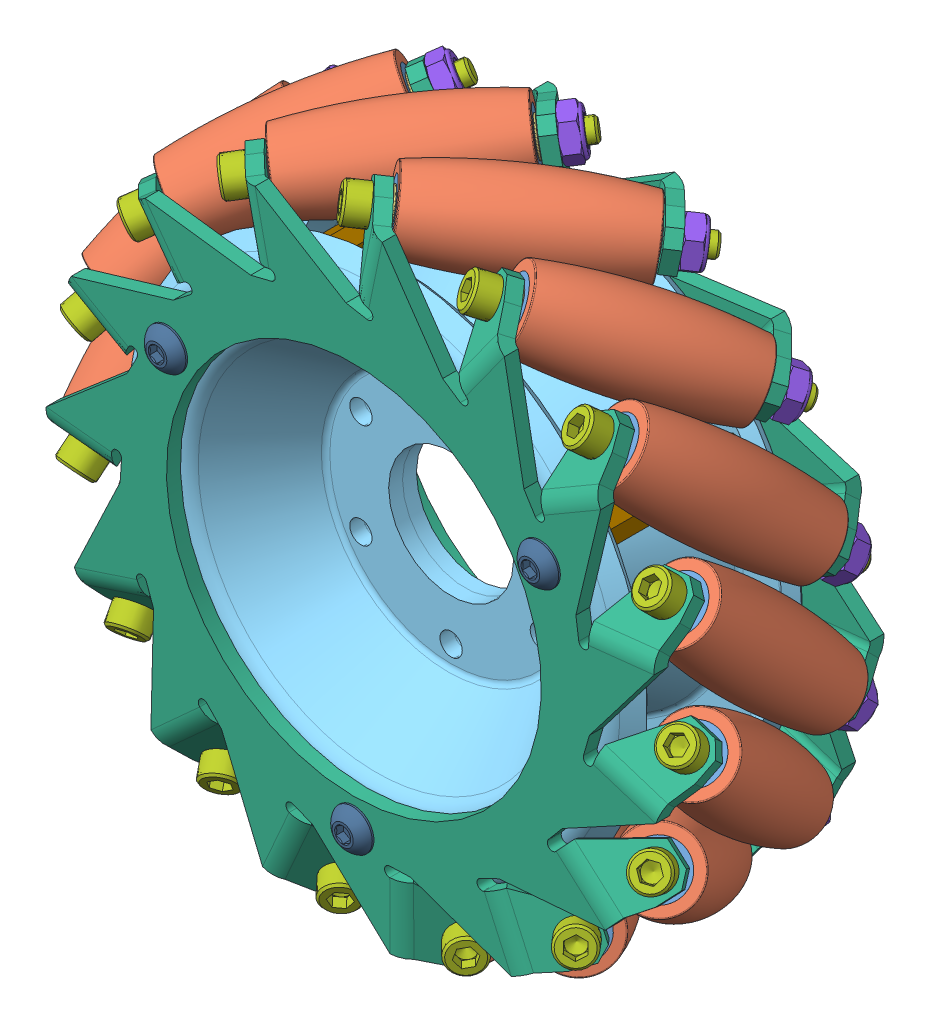
SolidWorks assembly am-3479La 6 SR Mecanum (LEFT with Standoffs), configuration Default. Lengths in mm.
Overall size (158.29 158.03 55.95).
134 component instances, 10 part files, 0 mates.
Components (placement in the parent):
- am-3479La 6 SR Mecanum Left with Standoffs.STEP-1: am-3479La 6 SR Mecanum Left with Standoffs.STEP [Default] at origin size (158.29 158.03 55.95)
  - am-3479_roller.STEP-1: am-3479_roller.STEP [Default] at (-1.2868 -63.2802 -0.1615) x (-0.034273 0.998836 0.033931) z (0.706278 0.048228 -0.70629) size (19.48 44.35 19.48)
    - am-3698_core PC.STEP-1: am-3698_core PC.STEP [Default] at (-2.9239 1.0394 0.8367) size (14.92 43.18 14.92)
    - am-3698_skin TPU v2.STEP-1: am-3698_skin TPU v2.STEP [Default] at (-2.9239 22.6294 0.8367) x (1 0 0) z (0 1 0) size (19.48 19.48 43.18)
    - am-0603 MBC Bushing MU04TH04.STEP-1: am-0603 MBC Bushing MU04TH04.STEP [Default] at (-2.9239 -20.9316 0.8367) x (0 1 0) z (0 0 1) size (6.35 7.94 7.94)
    - am-0603 MBC Bushing MU04TH04.STEP-2: am-0603 MBC Bushing MU04TH04.STEP [Default] at (-2.9239 16.6604 0.8367) x (0 1 0) z (-0.707574 0 0.70664) size (6.35 7.94 7.94)
    - am-0701a 6IN SR Roller Axle.STEP-1: am-0701a 6IN SR Roller Axle.STEP [Default] at (-2.9239 23.2136 0.8367) x (0 -1 0) z (0 0 1) size (44.35 6.35 6.35)
  - am-3479_roller-1.STEP-1: am-3479_roller-1.STEP [Default] at (-26.9139 -57.2859 -0.1615) x (0.374953 0.926423 0.033931) z (0.664833 -0.243211 -0.70629) size (19.48 44.35 19.48)
    - am-3698_core PC.STEP-1: am-3698_core PC.STEP [Default] at (-2.9239 1.0394 0.8367) size (14.92 43.18 14.92)
    - am-3698_skin TPU v2.STEP-1: am-3698_skin TPU v2.STEP [Default] at (-2.9239 22.6294 0.8367) x (1 0 0) z (0 1 0) size (19.48 19.48 43.18)
    - am-0603 MBC Bushing MU04TH04.STEP-1: am-0603 MBC Bushing MU04TH04.STEP [Default] at (-2.9239 -20.9316 0.8367) x (0 1 0) z (0 0 1) size (6.35 7.94 7.94)
    - am-0603 MBC Bushing MU04TH04.STEP-2: am-0603 MBC Bushing MU04TH04.STEP [Default] at (-2.9239 16.6604 0.8367) x (0 1 0) z (-0.707574 0 0.70664) size (6.35 7.94 7.94)
    - am-0701a 6IN SR Roller Axle.STEP-1: am-0701a 6IN SR Roller Axle.STEP [Default] at (-2.9239 23.2136 0.8367) x (0 -1 0) z (0 0 1) size (44.35 6.35 6.35)
  - am-3479_roller-2.STEP-1: am-3479_roller-2.STEP [Default] at (-47.8873 -41.3864 -0.1615) x (0.719347 0.693822 0.033931) z (0.508432 -0.492596 -0.70629) size (19.48 44.35 19.48)
    - am-3698_core PC.STEP-1: am-3698_core PC.STEP [Default] at (-2.9239 1.0394 0.8367) size (14.92 43.18 14.92)
    - am-3698_skin TPU v2.STEP-1: am-3698_skin TPU v2.STEP [Default] at (-2.9239 22.6294 0.8367) x (1 0 0) z (0 1 0) size (19.48 19.48 43.18)
    - am-0603 MBC Bushing MU04TH04.STEP-1: am-0603 MBC Bushing MU04TH04.STEP [Default] at (-2.9239 -20.9316 0.8367) x (0 1 0) z (0 0 1) size (6.35 7.94 7.94)
    - am-0603 MBC Bushing MU04TH04.STEP-2: am-0603 MBC Bushing MU04TH04.STEP [Default] at (-2.9239 16.6604 0.8367) x (0 1 0) z (-0.707574 0 0.70664) size (6.35 7.94 7.94)
    - am-0701a 6IN SR Roller Axle.STEP-1: am-0701a 6IN SR Roller Axle.STEP [Default] at (-2.9239 23.2136 0.8367) x (0 -1 0) z (0 0 1) size (44.35 6.35 6.35)
  - am-3479_roller-3.STEP-1: am-3479_roller-3.STEP [Default] at (-60.5806 -18.3309 -0.1615) x (0.939359 0.341253 0.033931) z (0.264119 -0.656807 -0.70629) size (19.48 44.35 19.48)
    - am-3698_core PC.STEP-1: am-3698_core PC.STEP [Default] at (-2.9239 1.0394 0.8367) size (14.92 43.18 14.92)
    - am-3698_skin TPU v2.STEP-1: am-3698_skin TPU v2.STEP [Default] at (-2.9239 22.6294 0.8367) x (1 0 0) z (0 1 0) size (19.48 19.48 43.18)
    - am-0603 MBC Bushing MU04TH04.STEP-1: am-0603 MBC Bushing MU04TH04.STEP [Default] at (-2.9239 -20.9316 0.8367) x (0 1 0) z (0 0 1) size (6.35 7.94 7.94)
    - am-0603 MBC Bushing MU04TH04.STEP-2: am-0603 MBC Bushing MU04TH04.STEP [Default] at (-2.9239 16.6604 0.8367) x (0 1 0) z (-0.707574 0 0.70664) size (6.35 7.94 7.94)
    - am-0701a 6IN SR Roller Axle.STEP-1: am-0701a 6IN SR Roller Axle.STEP [Default] at (-2.9239 23.2136 0.8367) x (0 -1 0) z (0 0 1) size (44.35 6.35 6.35)
  - am-3479_roller-4.STEP-1: am-3479_roller-4.STEP [Default] at (-62.799 7.8943 -0.1615) x (0.996947 -0.070321 0.033931) z (-0.025863 -0.70745 -0.70629) size (19.48 44.35 19.48)
    - am-3698_core PC.STEP-1: am-3698_core PC.STEP [Default] at (-2.9239 1.0394 0.8367) size (14.92 43.18 14.92)
    - am-3698_skin TPU v2.STEP-1: am-3698_skin TPU v2.STEP [Default] at (-2.9239 22.6294 0.8367) x (1 0 0) z (0 1 0) size (19.48 19.48 43.18)
    - am-0603 MBC Bushing MU04TH04.STEP-1: am-0603 MBC Bushing MU04TH04.STEP [Default] at (-2.9239 -20.9316 0.8367) x (0 1 0) z (0 0 1) size (6.35 7.94 7.94)
    - am-0603 MBC Bushing MU04TH04.STEP-2: am-0603 MBC Bushing MU04TH04.STEP [Default] at (-2.9239 16.6604 0.8367) x (0 1 0) z (-0.707574 0 0.70664) size (6.35 7.94 7.94)
    - am-0701a 6IN SR Roller Axle.STEP-1: am-0701a 6IN SR Roller Axle.STEP [Default] at (-2.9239 23.2136 0.8367) x (0 -1 0) z (0 0 1) size (44.35 6.35 6.35)
  - am-3479_roller-5.STEP-1: am-3479_roller-5.STEP [Default] at (-54.1588 32.7544 -0.1615) x (0.882154 -0.469737 0.033931) z (-0.311373 -0.635768 -0.70629) size (19.48 44.35 19.48)
    - am-3698_core PC.STEP-1: am-3698_core PC.STEP [Default] at (-2.9239 1.0394 0.8367) size (14.92 43.18 14.92)
    - am-3698_skin TPU v2.STEP-1: am-3698_skin TPU v2.STEP [Default] at (-2.9239 22.6294 0.8367) x (1 0 0) z (0 1 0) size (19.48 19.48 43.18)
    - am-0603 MBC Bushing MU04TH04.STEP-1: am-0603 MBC Bushing MU04TH04.STEP [Default] at (-2.9239 -20.9316 0.8367) x (0 1 0) z (0 0 1) size (6.35 7.94 7.94)
    - am-0603 MBC Bushing MU04TH04.STEP-2: am-0603 MBC Bushing MU04TH04.STEP [Default] at (-2.9239 16.6604 0.8367) x (0 1 0) z (-0.707574 0 0.70664) size (6.35 7.94 7.94)
    - am-0701a 6IN SR Roller Axle.STEP-1: am-0701a 6IN SR Roller Axle.STEP [Default] at (-2.9239 23.2136 0.8367) x (0 -1 0) z (0 0 1) size (44.35 6.35 6.35)
  - am-3479_roller-6.STEP-1: am-3479_roller-6.STEP [Default] at (-36.1541 51.9511 -0.1615) x (0.614829 -0.78793 0.033931) z (-0.543043 -0.454157 -0.70629) size (19.48 44.35 19.48)
    - am-3698_core PC.STEP-1: am-3698_core PC.STEP [Default] at (-2.9239 1.0394 0.8367) size (14.92 43.18 14.92)
    - am-3698_skin TPU v2.STEP-1: am-3698_skin TPU v2.STEP [Default] at (-2.9239 22.6294 0.8367) x (1 0 0) z (0 1 0) size (19.48 19.48 43.18)
    - am-0603 MBC Bushing MU04TH04.STEP-1: am-0603 MBC Bushing MU04TH04.STEP [Default] at (-2.9239 -20.9316 0.8367) x (0 1 0) z (0 0 1) size (6.35 7.94 7.94)
    - am-0603 MBC Bushing MU04TH04.STEP-2: am-0603 MBC Bushing MU04TH04.STEP [Default] at (-2.9239 16.6604 0.8367) x (0 1 0) z (-0.707574 0 0.70664) size (6.35 7.94 7.94)
    - am-0701a 6IN SR Roller Axle.STEP-1: am-0701a 6IN SR Roller Axle.STEP [Default] at (-2.9239 23.2136 0.8367) x (0 -1 0) z (0 0 1) size (44.35 6.35 6.35)
  - am-3479_roller-7.STEP-1: am-3479_roller-7.STEP [Default] at (-11.898 62.1649 -0.1615) x (0.241194 -0.969884 0.033931) z (-0.680817 -0.194017 -0.70629) size (19.48 44.35 19.48)
    - am-3698_core PC.STEP-1: am-3698_core PC.STEP [Default] at (-2.9239 1.0394 0.8367) size (14.92 43.18 14.92)
    - am-3698_skin TPU v2.STEP-1: am-3698_skin TPU v2.STEP [Default] at (-2.9239 22.6294 0.8367) x (1 0 0) z (0 1 0) size (19.48 19.48 43.18)
    - am-0603 MBC Bushing MU04TH04.STEP-1: am-0603 MBC Bushing MU04TH04.STEP [Default] at (-2.9239 -20.9316 0.8367) x (0 1 0) z (0 0 1) size (6.35 7.94 7.94)
    - am-0603 MBC Bushing MU04TH04.STEP-2: am-0603 MBC Bushing MU04TH04.STEP [Default] at (-2.9239 16.6604 0.8367) x (0 1 0) z (-0.707574 0 0.70664) size (6.35 7.94 7.94)
    - am-0701a 6IN SR Roller Axle.STEP-1: am-0701a 6IN SR Roller Axle.STEP [Default] at (-2.9239 23.2136 0.8367) x (0 -1 0) z (0 0 1) size (44.35 6.35 6.35)
  - am-3479_roller-8.STEP-1: am-3479_roller-8.STEP [Default] at (14.4153 61.6298 -0.1615) x (-0.174146 -0.984135 0.033931) z (-0.700871 0.09967 -0.70629) size (19.48 44.35 19.48)
    - am-3698_core PC.STEP-1: am-3698_core PC.STEP [Default] at (-2.9239 1.0394 0.8367) size (14.92 43.18 14.92)
    - am-3698_skin TPU v2.STEP-1: am-3698_skin TPU v2.STEP [Default] at (-2.9239 22.6294 0.8367) x (1 0 0) z (0 1 0) size (19.48 19.48 43.18)
    - am-0603 MBC Bushing MU04TH04.STEP-1: am-0603 MBC Bushing MU04TH04.STEP [Default] at (-2.9239 -20.9316 0.8367) x (0 1 0) z (0 0 1) size (6.35 7.94 7.94)
    - am-0603 MBC Bushing MU04TH04.STEP-2: am-0603 MBC Bushing MU04TH04.STEP [Default] at (-2.9239 16.6604 0.8367) x (0 1 0) z (-0.707574 0 0.70664) size (6.35 7.94 7.94)
    - am-0701a 6IN SR Roller Axle.STEP-1: am-0701a 6IN SR Roller Axle.STEP [Default] at (-2.9239 23.2136 0.8367) x (0 -1 0) z (0 0 1) size (44.35 6.35 6.35)
  - am-3479_roller-9.STEP-1: am-3479_roller-9.STEP [Default] at (38.2362 50.4384 -0.1615) x (-0.559374 -0.828221 0.033931) z (-0.599738 0.376123 -0.70629) size (19.48 44.35 19.48)
    - am-3698_core PC.STEP-1: am-3698_core PC.STEP [Default] at (-2.9239 1.0394 0.8367) size (14.92 43.18 14.92)
    - am-3698_skin TPU v2.STEP-1: am-3698_skin TPU v2.STEP [Default] at (-2.9239 22.6294 0.8367) x (1 0 0) z (0 1 0) size (19.48 19.48 43.18)
    - am-0603 MBC Bushing MU04TH04.STEP-1: am-0603 MBC Bushing MU04TH04.STEP [Default] at (-2.9239 -20.9316 0.8367) x (0 1 0) z (0 0 1) size (6.35 7.94 7.94)
    - am-0603 MBC Bushing MU04TH04.STEP-2: am-0603 MBC Bushing MU04TH04.STEP [Default] at (-2.9239 16.6604 0.8367) x (0 1 0) z (-0.707574 0 0.70664) size (6.35 7.94 7.94)
    - am-0701a 6IN SR Roller Axle.STEP-1: am-0701a 6IN SR Roller Axle.STEP [Default] at (-2.9239 23.2136 0.8367) x (0 -1 0) z (0 0 1) size (44.35 6.35 6.35)
  - am-3479_roller-10.STEP-1: am-3479_roller-10.STEP [Default] at (55.4456 30.5257 -0.1615) x (-0.847881 -0.5291 0.033931) z (-0.394905 0.587541 -0.70629) size (19.48 44.35 19.48)
    - am-3698_core PC.STEP-1: am-3698_core PC.STEP [Default] at (-2.9239 1.0394 0.8367) size (14.92 43.18 14.92)
    - am-3698_skin TPU v2.STEP-1: am-3698_skin TPU v2.STEP [Default] at (-2.9239 22.6294 0.8367) x (1 0 0) z (0 1 0) size (19.48 19.48 43.18)
    - am-0603 MBC Bushing MU04TH04.STEP-1: am-0603 MBC Bushing MU04TH04.STEP [Default] at (-2.9239 -20.9316 0.8367) x (0 1 0) z (0 0 1) size (6.35 7.94 7.94)
    - am-0603 MBC Bushing MU04TH04.STEP-2: am-0603 MBC Bushing MU04TH04.STEP [Default] at (-2.9239 16.6604 0.8367) x (0 1 0) z (-0.707574 0 0.70664) size (6.35 7.94 7.94)
    - am-0701a 6IN SR Roller Axle.STEP-1: am-0701a 6IN SR Roller Axle.STEP [Default] at (-2.9239 23.2136 0.8367) x (0 -1 0) z (0 0 1) size (44.35 6.35 6.35)
  - am-3479_roller-11.STEP-1: am-3479_roller-11.STEP [Default] at (63.068 5.3349 -0.1615) x (-0.989782 -0.138492 0.033931) z (-0.121789 0.697368 -0.70629) size (19.48 44.35 19.48)
    - am-3698_core PC.STEP-1: am-3698_core PC.STEP [Default] at (-2.9239 1.0394 0.8367) size (14.92 43.18 14.92)
    - am-3698_skin TPU v2.STEP-1: am-3698_skin TPU v2.STEP [Default] at (-2.9239 22.6294 0.8367) x (1 0 0) z (0 1 0) size (19.48 19.48 43.18)
    - am-0603 MBC Bushing MU04TH04.STEP-1: am-0603 MBC Bushing MU04TH04.STEP [Default] at (-2.9239 -20.9316 0.8367) x (0 1 0) z (0 0 1) size (6.35 7.94 7.94)
    - am-0603 MBC Bushing MU04TH04.STEP-2: am-0603 MBC Bushing MU04TH04.STEP [Default] at (-2.9239 16.6604 0.8367) x (0 1 0) z (-0.707574 0 0.70664) size (6.35 7.94 7.94)
    - am-0701a 6IN SR Roller Axle.STEP-1: am-0701a 6IN SR Roller Axle.STEP [Default] at (-2.9239 23.2136 0.8367) x (0 -1 0) z (0 0 1) size (44.35 6.35 6.35)
  - am-3479_roller-12.STEP-1: am-3479_roller-12.STEP [Default] at (59.7854 -20.7784 -0.1615) x (-0.960541 0.276062 0.033931) z (0.172385 0.686613 -0.70629) size (19.48 44.35 19.48)
    - am-3698_core PC.STEP-1: am-3698_core PC.STEP [Default] at (-2.9239 1.0394 0.8367) size (14.92 43.18 14.92)
    - am-3698_skin TPU v2.STEP-1: am-3698_skin TPU v2.STEP [Default] at (-2.9239 22.6294 0.8367) x (1 0 0) z (0 1 0) size (19.48 19.48 43.18)
    - am-0603 MBC Bushing MU04TH04.STEP-1: am-0603 MBC Bushing MU04TH04.STEP [Default] at (-2.9239 -20.9316 0.8367) x (0 1 0) z (0 0 1) size (6.35 7.94 7.94)
    - am-0603 MBC Bushing MU04TH04.STEP-2: am-0603 MBC Bushing MU04TH04.STEP [Default] at (-2.9239 16.6604 0.8367) x (0 1 0) z (-0.707574 0 0.70664) size (6.35 7.94 7.94)
    - am-0701a 6IN SR Roller Axle.STEP-1: am-0701a 6IN SR Roller Axle.STEP [Default] at (-2.9239 23.2136 0.8367) x (0 -1 0) z (0 0 1) size (44.35 6.35 6.35)
  - am-3479_roller-13.STEP-1: am-3479_roller-13.STEP [Default] at (46.1653 -43.2989 -0.1615) x (-0.765213 0.642882 0.033931) z (0.436752 0.557137 -0.70629) size (19.48 44.35 19.48)
    - am-3698_core PC.STEP-1: am-3698_core PC.STEP [Default] at (-2.9239 1.0394 0.8367) size (14.92 43.18 14.92)
    - am-3698_skin TPU v2.STEP-1: am-3698_skin TPU v2.STEP [Default] at (-2.9239 22.6294 0.8367) x (1 0 0) z (0 1 0) size (19.48 19.48 43.18)
    - am-0603 MBC Bushing MU04TH04.STEP-1: am-0603 MBC Bushing MU04TH04.STEP [Default] at (-2.9239 -20.9316 0.8367) x (0 1 0) z (0 0 1) size (6.35 7.94 7.94)
    - am-0603 MBC Bushing MU04TH04.STEP-2: am-0603 MBC Bushing MU04TH04.STEP [Default] at (-2.9239 16.6604 0.8367) x (0 1 0) z (-0.707574 0 0.70664) size (6.35 7.94 7.94)
    - am-0701a 6IN SR Roller Axle.STEP-1: am-0701a 6IN SR Roller Axle.STEP [Default] at (-2.9239 23.2136 0.8367) x (0 -1 0) z (0 0 1) size (44.35 6.35 6.35)
  - am-3479_roller-14.STEP-1: am-3479_roller-14.STEP [Default] at (24.5628 -58.3327 -0.1615) x (-0.437573 0.898542 0.033931) z (0.625601 0.331327 -0.70629) size (19.48 44.35 19.48)
    - am-3698_core PC.STEP-1: am-3698_core PC.STEP [Default] at (-2.9239 1.0394 0.8367) size (14.92 43.18 14.92)
    - am-3698_skin TPU v2.STEP-1: am-3698_skin TPU v2.STEP [Default] at (-2.9239 22.6294 0.8367) x (1 0 0) z (0 1 0) size (19.48 19.48 43.18)
    - am-0603 MBC Bushing MU04TH04.STEP-1: am-0603 MBC Bushing MU04TH04.STEP [Default] at (-2.9239 -20.9316 0.8367) x (0 1 0) z (0 0 1) size (6.35 7.94 7.94)
    - am-0603 MBC Bushing MU04TH04.STEP-2: am-0603 MBC Bushing MU04TH04.STEP [Default] at (-2.9239 16.6604 0.8367) x (0 1 0) z (-0.707574 0 0.70664) size (6.35 7.94 7.94)
    - am-0701a 6IN SR Roller Axle.STEP-1: am-0701a 6IN SR Roller Axle.STEP [Default] at (-2.9239 23.2136 0.8367) x (0 -1 0) z (0 0 1) size (44.35 6.35 6.35)
  - ip-3479a_hub.STEP-1: ip-3479a_hub.STEP [Default] x (0 0 1) z (1 0 0) size (22.23 118.71 118.71)
  - ip-3479a_hub.STEP-2: ip-3479a_hub.STEP [Default] x (0 0 -1) z (-1 0 0) size (22.23 118.71 118.71)
  - am-0676a Left Plate HD.STEP-1: am-0676a Left Plate HD.STEP [Default] at (0 0 23.114) x (-0.999437 -0.033548 0) z (0 0 1) size (146.64 146.22 13.05)
  - am-0676a Left Plate HD.STEP-2: am-0676a Left Plate HD.STEP [Default] at (0 0 -23.114) x (0.99946 -0.032864 0) z (0 0 -1) size (146.64 146.22 13.05)
  - 10-32x2250_shcs_HX-SHCS 0.19-32x1.375x1-C.STEP-1: 10-32x2250_shcs_HX-SHCS 0.19-32x1.375x1-C.STEP [Default] at (21.4977 -66.1527 21.2417) x (-0.707105 -0.000242 -0.707109) z (0.143048 -0.979373 -0.142712) size (61.98 7.94 7.94)
  - 10-32 Nylock Jam Nut_90633A411.STEP-1: 10-32 Nylock Jam Nut_90633A411.STEP [Default] at (-17.791 -66.1662 -18.0472) x (0.176781 0.968184 -0.177112) z (-0.684654 0.25024 0.684564) size (9.55 4.38 11.02)
  - 10-32 Nylock Jam Nut_90633A411.STEP-2: 10-32 Nylock Jam Nut_90633A411.STEP [Default] at (-43.1651 -53.2096 -18.0472) x (0.555294 0.812576 -0.177112) z (-0.523681 0.50708 0.684564) size (9.55 4.38 11.02)
  - 10-32 Nylock Jam Nut_90633A411.STEP-3: 10-32 Nylock Jam Nut_90633A411.STEP [Default] at (-61.0755 -31.0525 -18.0472) x (0.837791 0.516467 -0.177112) z (-0.272158 0.676241 0.684564) size (9.55 4.38 11.02)
  - 10-32 Nylock Jam Nut_90633A411.STEP-4: 10-32 Nylock Jam Nut_90633A411.STEP [Default] at (-68.4255 -3.5263 -18.0472) x (0.975426 0.131056 -0.177112) z (0.026423 0.728473 0.684564) size (9.55 4.38 11.02)
  - 10-32 Nylock Jam Nut_90633A411.STEP-5: 10-32 Nylock Jam Nut_90633A411.STEP [Default] at (-63.9441 24.6098 -18.0472) x (0.944401 -0.277016 -0.177112) z (0.320435 0.654747 0.684564) size (9.55 4.38 11.02)
  - 10-32 Nylock Jam Nut_90633A411.STEP-6: 10-32 Nylock Jam Nut_90633A411.STEP [Default] at (-48.4061 48.4905 -18.0472) x (0.750081 -0.637189 -0.177112) z (0.559041 0.467808 0.684564) size (9.55 4.38 11.02)
  - 10-32 Nylock Jam Nut_90633A411.STEP-7: 10-32 Nylock Jam Nut_90633A411.STEP [Default] at (-24.4983 63.9868 -18.0472) x (0.426065 -0.887187 -0.177112) z (0.700984 0.199981 0.684564) size (9.55 4.38 11.02)
  - 10-32 Nylock Jam Nut_90633A411.STEP-8: 10-32 Nylock Jam Nut_90633A411.STEP [Default] at (3.6455 68.4192 -18.0472) x (0.028379 -0.983782 -0.177112) z (0.721721 -0.102424 0.684564) size (9.55 4.38 11.02)
  - 10-32 Nylock Jam Nut_90633A411.STEP-9: 10-32 Nylock Jam Nut_90633A411.STEP [Default] at (31.1589 61.0213 -18.0472) x (-0.374215 -0.910272 -0.177112) z (0.617665 -0.387119 0.684564) size (9.55 4.38 11.02)
  - 10-32 Nylock Jam Nut_90633A411.STEP-10: 10-32 Nylock Jam Nut_90633A411.STEP [Default] at (53.2847 43.0723 -18.0472) x (-0.712103 -0.679368 -0.177112) z (0.40681 -0.604878 0.684564) size (9.55 4.38 11.02)
  - 10-32 Nylock Jam Nut_90633A411.STEP-11: 10-32 Nylock Jam Nut_90633A411.STEP [Default] at (66.1971 17.6757 -18.0472) x (-0.926862 -0.330995 -0.177112) z (0.125613 -0.718048 0.684564) size (9.55 4.38 11.02)
  - 10-32 Nylock Jam Nut_90633A411.STEP-12: 10-32 Nylock Jam Nut_90633A411.STEP [Default] at (67.6634 -10.7773 -18.0472) x (-0.981359 0.07461 -0.177112) z (-0.177303 -0.707061 0.684564) size (9.55 4.38 11.02)
  - 10-32 Nylock Jam Nut_90633A411.STEP-13: 10-32 Nylock Jam Nut_90633A411.STEP [Default] at (57.4301 -37.3667 -18.0472) x (-0.866169 0.467314 -0.177112) z (-0.449562 -0.573817 0.684564) size (9.55 4.38 11.02)
  - 10-32 Nylock Jam Nut_90633A411.STEP-14: 10-32 Nylock Jam Nut_90633A411.STEP [Default] at (37.2666 -57.4951 -18.0472) x (-0.601211 0.779216 -0.177112) z (-0.644088 -0.341354 0.684564) size (9.55 4.38 11.02)
  - 10-32 Nylock Jam Nut_90633A411.STEP-15: 10-32 Nylock Jam Nut_90633A411.STEP [Default] at (10.6594 -67.6821 -18.0472) x (-0.232298 0.956383 -0.177112) z (-0.727245 -0.049868 0.684564) size (9.55 4.38 11.02)
  - 10-32x2250_shcs_HX-SHCS 0.19-32x1.375x1-C.STEP-2: 10-32x2250_shcs_HX-SHCS 0.19-32x1.375x1-C.STEP [Default] at (-7.2676 -69.1774 21.2417) x (-0.646071 0.287384 -0.707109) z (-0.267666 -0.952884 -0.142712) size (61.98 7.94 7.94)
  - 10-32x2250_shcs_HX-SHCS 0.19-32x1.375x1-C.STEP-3: 10-32x2250_shcs_HX-SHCS 0.19-32x1.375x1-C.STEP [Default] at (-34.7763 -60.2407 21.2417) x (-0.473325 0.525319 -0.707109) z (-0.632098 -0.761633 -0.142712) size (61.98 7.94 7.94)
  - 10-32x2250_shcs_HX-SHCS 0.19-32x1.375x1-C.STEP-4: 10-32x2250_shcs_HX-SHCS 0.19-32x1.375x1-C.STEP [Default] at (-56.2718 -40.8879 21.2417) x (-0.218738 0.672422 -0.707109) z (-0.887234 -0.438689 -0.142712) size (61.98 7.94 7.94)
  - 10-32x2250_shcs_HX-SHCS 0.19-32x1.375x1-C.STEP-5: 10-32x2250_shcs_HX-SHCS 0.19-32x1.375x1-C.STEP [Default] at (-68.0375 -14.4651 21.2417) x (0.073672 0.703256 -0.707109) z (-0.98896 -0.039892 -0.142712) size (61.98 7.94 7.94)
  - 10-32x2250_shcs_HX-SHCS 0.19-32x1.375x1-C.STEP-6: 10-32x2250_shcs_HX-SHCS 0.19-32x1.375x1-C.STEP [Default] at (-68.0388 14.4588 21.2417) x (0.353343 0.612492 -0.707109) z (-0.919685 0.365803 -0.142712) size (61.98 7.94 7.94)
  - 10-32x2250_shcs_HX-SHCS 0.19-32x1.375x1-C.STEP-7: 10-32x2250_shcs_HX-SHCS 0.19-32x1.375x1-C.STEP [Default] at (-56.2756 40.8826 21.2417) x (0.571917 0.415821 -0.707109) z (-0.691389 0.708248 -0.142712) size (61.98 7.94 7.94)
  - 10-32x2250_shcs_HX-SHCS 0.19-32x1.375x1-C.STEP-8: 10-32x2250_shcs_HX-SHCS 0.19-32x1.375x1-C.STEP [Default] at (-34.7819 60.2375 21.2417) x (0.691602 0.147252 -0.707109) z (-0.343545 0.92823 -0.142712) size (61.98 7.94 7.94)
  - 10-32x2250_shcs_HX-SHCS 0.19-32x1.375x1-C.STEP-9: 10-32x2250_shcs_HX-SHCS 0.19-32x1.375x1-C.STEP [Default] at (-7.274 69.1768 21.2417) x (0.691703 -0.146778 -0.707109) z (0.063701 0.987712 -0.142712) size (61.98 7.94 7.94)
  - 10-32x2250_shcs_HX-SHCS 0.19-32x1.375x1-C.STEP-10: 10-32x2250_shcs_HX-SHCS 0.19-32x1.375x1-C.STEP [Default] at (21.4916 66.1547 21.2417) x (0.572202 -0.41543 -0.707109) z (0.459933 0.876411 -0.142712) size (61.98 7.94 7.94)
  - 10-32x2250_shcs_HX-SHCS 0.19-32x1.375x1-C.STEP-11: 10-32x2250_shcs_HX-SHCS 0.19-32x1.375x1-C.STEP [Default] at (46.5411 51.6939 21.2417) x (0.353762 -0.612249 -0.707109) z (0.776638 0.613569 -0.142712) size (61.98 7.94 7.94)
  - 10-32x2250_shcs_HX-SHCS 0.19-32x1.375x1-C.STEP-12: 10-32x2250_shcs_HX-SHCS 0.19-32x1.375x1-C.STEP [Default] at (63.5432 28.2948 21.2417) x (0.074153 -0.703206 -0.707109) z (0.959055 0.244637 -0.142712) size (61.98 7.94 7.94)
  - 10-32x2250_shcs_HX-SHCS 0.19-32x1.375x1-C.STEP-13: 10-32x2250_shcs_HX-SHCS 0.19-32x1.375x1-C.STEP [Default] at (69.5581 0.0032 21.2417) x (-0.218277 -0.672571 -0.707109) z (0.975643 -0.166596 -0.142712) size (61.98 7.94 7.94)
  - 10-32x2250_shcs_HX-SHCS 0.19-32x1.375x1-C.STEP-14: 10-32x2250_shcs_HX-SHCS 0.19-32x1.375x1-C.STEP [Default] at (63.5458 -28.2889 21.2417) x (-0.472965 -0.525643 -0.707109) z (0.823533 -0.549023 -0.142712) size (61.98 7.94 7.94)
  - 10-32x2250_shcs_HX-SHCS 0.19-32x1.375x1-C.STEP-15: 10-32x2250_shcs_HX-SHCS 0.19-32x1.375x1-C.STEP [Default] at (46.5459 -51.6896 21.2417) x (-0.645874 -0.287827 -0.707109) z (0.529027 -0.836519 -0.142712) size (61.98 7.94 7.94)
  - 91780A190_ALUM FEM THRDED HEX STANDOFF_91780A190.STEP-1: 91780A190_ALUM FEM THRDED HEX STANDOFF_91780A190.STEP [Default] at (0 -49.2125 0) size (10.44 13.9 43.26)
  - 91780A190_ALUM FEM THRDED HEX STANDOFF_91780A190.STEP-2: 91780A190_ALUM FEM THRDED HEX STANDOFF_91780A190.STEP [Default] at (-42.6193 24.6062 0) size (10.44 13.9 43.26)
  - 91780A190_ALUM FEM THRDED HEX STANDOFF_91780A190.STEP-3: 91780A190_ALUM FEM THRDED HEX STANDOFF_91780A190.STEP [Default] at (42.6193 24.6062 0) size (10.44 13.9 43.26)
  - BHCS 10-32 x 0.500_91255A265.STEP-1: BHCS 10-32 x 0.500_91255A265.STEP [Default] at (-42.6193 24.6062 27.9654) size (9.17 9.17 15.27)
  - BHCS 10-32 x 0.500_91255A265.STEP-2: BHCS 10-32 x 0.500_91255A265.STEP [Default] at (42.6193 24.6062 27.9654) size (9.17 9.17 15.27)
  - BHCS 10-32 x 0.500_91255A265.STEP-3: BHCS 10-32 x 0.500_91255A265.STEP [Default] at (0 -49.2125 27.9654) size (9.17 9.17 15.27)
  - BHCS 10-32 x 0.500_91255A265.STEP-4: BHCS 10-32 x 0.500_91255A265.STEP [Default] at (42.6024 24.6354 -27.9654) x (0.923728 0.383049 0) z (0 0 -1) size (9.17 9.17 15.27)
  - BHCS 10-32 x 0.500_91255A265.STEP-5: BHCS 10-32 x 0.500_91255A265.STEP [Default] at (-42.6361 24.5771 -27.9654) x (0.923728 0.383049 0) z (0 0 -1) size (9.17 9.17 15.27)
  - BHCS 10-32 x 0.500_91255A265.STEP-6: BHCS 10-32 x 0.500_91255A265.STEP [Default] at (0.0337 -49.2125 -27.9654) x (0.923728 0.383049 0) z (0 0 -1) size (9.17 9.17 15.27)
